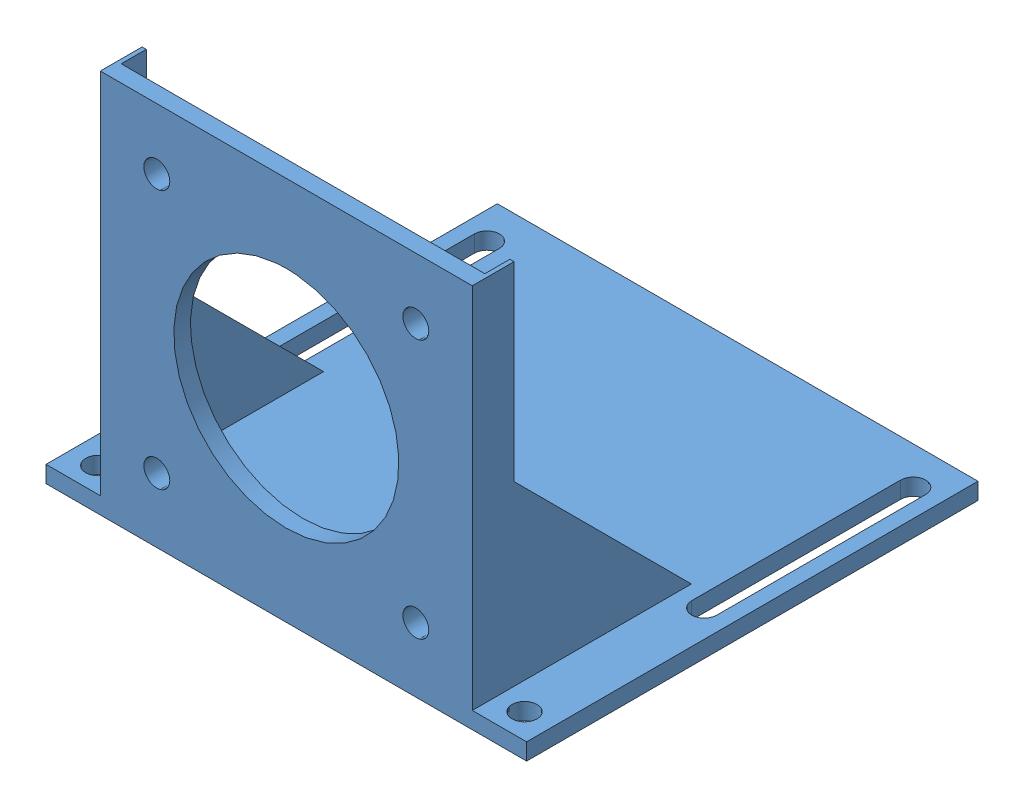
SolidWorks assembly Nema17-StepperMotor + Bracket, configuration Default. Lengths in mm.
Overall size (57.5 46 54).
2 component instances, 2 part files, 7 mates.
Components (placement in the parent):
- StepperMotor-MMC(6627T64)-1: StepperMotor-MMC(6627T64) [6627T64] at (21.209 21.209 47.45) size (42.42 43.14 71.45) (hidden)
- Nema17-StepperMotor Bracket-1: Nema17-StepperMotor Bracket [Default] at (21.209 0 47.45) x (-1 0 0) z (0 -1 0) size (57.5 54 46)
Mates (geometry in assembly coordinates):
- InPlace1: in place: plane of ? through (3.5655 -2.5846 51.7641) normal (0 -1 0); plane of ? through (0 -2.5846 0) normal (0 -1 0); moOrthogonalPlaneRef_w of ? through (3.5655 -2.5846 51.7641) normal (0 -1 0); plane of ? through (0 -2.5846 0) normal (0 0 -1); plane of ? through (3.5655 -2.5846 51.7641) normal (0 -1 0); plane of ? through (0 -2.5846 0) normal (-1 0 0); plane of StepperMotor-MMC(6627T64)-1 through (35.0928 0 39.8808) normal (0 -1 0); unknown of Nema17-StepperMotor Bracket-1
- Coincident1: coincident aligned: plane of StepperMotor-MMC(6627T64)-1; plane of Nema17-StepperMotor Bracket-1
- Coincident2: coincident aligned: moOrthogonalPlaneRef_w of StepperMotor-MMC(6627T64)-1 through (21.209 0 47.45) normal (0 0 -1); plane of Nema17-StepperMotor Bracket-1 through (21.209 0 47.45) normal (0 0 -1)
- Coincident3: coincident anti-aligned: moOrthogonalPlaneRef_w of StepperMotor-MMC(6627T64)-1 through (21.209 0 47.45) normal (1 0 0); plane of Nema17-StepperMotor Bracket-1 through (21.209 0 47.45) normal (-1 0 0)
- Coincident4: coincident anti-aligned: plane of StepperMotor-MMC(6627T64)-1 through (35.0928 0 39.8808) normal (0 -1 0)
- Coincident5: coincident anti-aligned: plane of StepperMotor-MMC(6627T64)-1 through (0 7.3252 39.8808) normal (-1 0 0)
- Coincident6: coincident anti-aligned: plane of StepperMotor-MMC(6627T64)-1 through (21.209 21.209 0) normal (0 0 -1)
